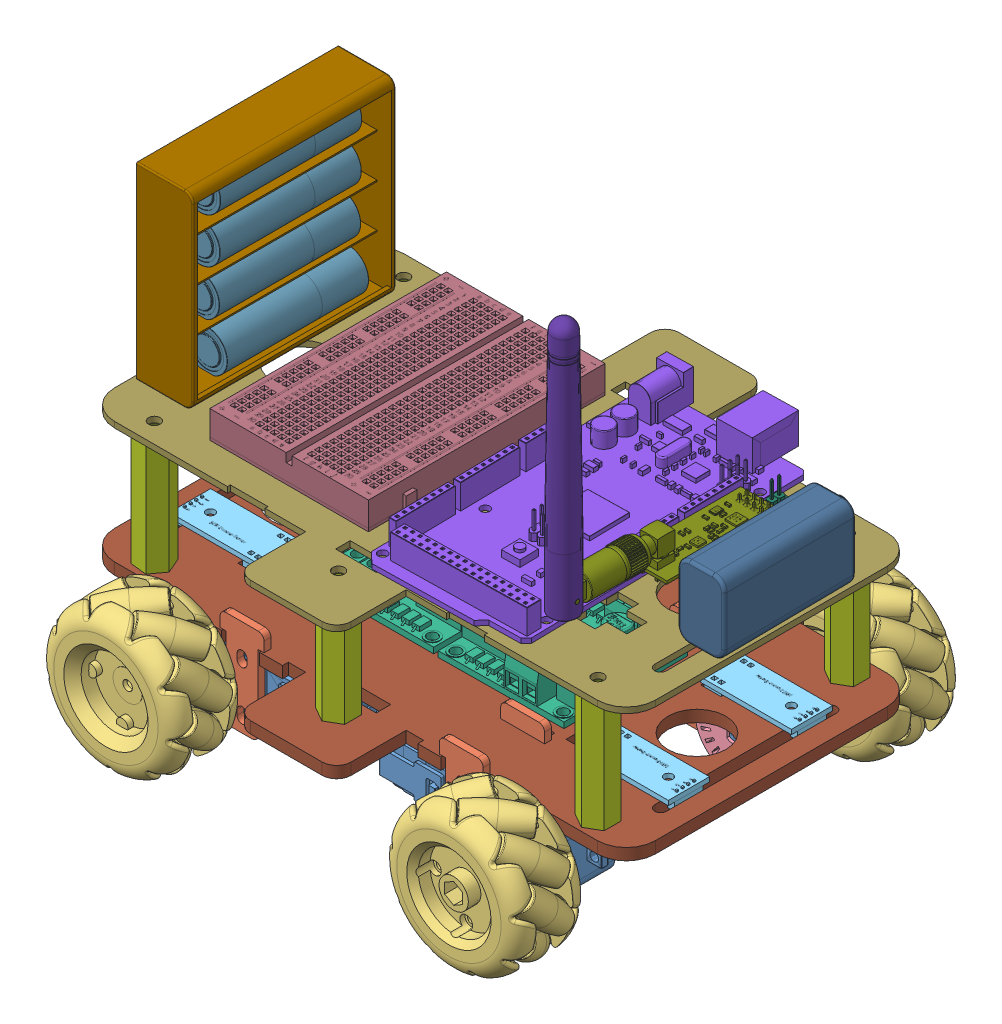
SolidWorks assembly RobotCarAssembly, configuration Default. Lengths in mm.
Overall size (187.94 185.46 154.36).
45 component instances, 17 part files, 43 mates.
Components (placement in the parent):
- Motor-1: Motor [Default] at (-116.3698 50.7185 244.6389) x (0 0 -1) z (1 0 0) size (37.1 22.45 70.35)
- Motor Stand-5: Motor Stand [Default] at (-128.5831 49.3185 244.6389) x (0 1 0) z (-1 0 0) size (33.3 2.4 15.15)
- Motor Stand-6: Motor Stand [Default] at (-128.5831 49.3185 223.4389) x (0 1 0) z (-1 0 0) size (33.3 2.4 15.15)
- Mecanum Left-1: Mecanum Left [Default] at (-142.3698 61.9185 266.4618) x (0 1 0) z (1 0 0) size (49.38 25 49.17)
- encoder20p-2: encoder20p [Predeterminado] at (-142.7381 61.8113 218.2185) x (1 0 0) z (0 0 -1) size (25.6 25.6 3.5)
- Lm393 Motor Speed Measuring Sensor Module-2: Lm393 Motor Speed Measuring Sensor Module [Default] at (-153.6231 78.7637 216.7144) x (-1 0 0) z (0 0 1) size (38.1 12.3 14.2)
- L298N-2: L298N [Default] at (-60.6738 77.1185 196.6466) x (-0.009989 0 -0.99995) z (0.99995 0 -0.009989) size (43 28.01 43)
- L298N-3: L298N [Default] at (-105.3237 77.1185 196.5696) x (0 0 1) z (-1 0 0) size (43 28.01 43)
- StandOffs-1: StandOffs [Default] at (-159.6669 77.1185 238.6389) x (-0.916026 0 0.401119) z (0 1 0) size (10 11.55 40)
- StandOffs-2: StandOffs [Default] at (-6.5177 77.1185 152.5697) x (-1 0 0) z (0 1 0) size (10 11.55 40)
- StandOffs-3: StandOffs [Default] at (-159.6669 77.1185 152.5697) x (-0.989331 0 -0.145683) z (0 1 0) size (10 11.55 40)
- StandOffs-4: StandOffs [Default] at (-6.5177 77.1185 238.6389) x (-1 0 0) z (0 1 0) size (10 11.55 40)
- StandOffs-5: StandOffs [Default] at (-83.0923 77.1185 251.6389) x (-1 0 0) z (0 1 0) size (10 11.55 40)
- StandOffs-6: StandOffs [Default] at (-83.0923 77.1185 139.6389) x (-1 0 0) z (0 1 0) size (10 11.55 40)
- Arduino Mega 2560-1: Arduino Mega 2560 [Default] at (-55.6757 120.7695 194.1341) x (-0.018928 0 -0.999821) z (0 -1 0) size (107.95 53.42 12.95)
- Battery Holder-1: Battery Holder [Default] at (-175.0329 151.6185 194.4484) x (0 -1 0) z (0 0 1) size (65 19.5 70)
- 9V-2-1: 9V-2 [Default] at (3.4952 131.6185 213.1599) x (0 -1 0) z (0.999927 0 -0.012056) size (25 49.55 16)
- ChassisBottom-1: ChassisBottom [LH] at (-87.5177 77.1185 196.2389) x (0 0 -1) z (0 -1 0) size (148 186.7 4)
- Motor-2: Motor [Default] at (-116.3698 73.1185 146.3201) x (0 0 1) z (1 0 0) size (37.1 22.45 70.35)
- Lm393 Motor Speed Measuring Sensor Module-3: Lm393 Motor Speed Measuring Sensor Module [Default] at (-153.6231 78.7637 174.2446) x (-1 0 0) z (0 0 1) size (38.1 12.3 14.2)
- encoder20p-3: encoder20p [Predeterminado] at (-142.7381 61.8113 172.7404) x (-1 0 0) z (0 0 1) size (25.6 25.6 3.5)
- Mecanum Left-2: Mecanum Left [Default] at (-142.3698 61.9185 137.0971) x (0 1 0) z (1 0 0) size (49.38 25 49.17)
- Motor Stand-7: Motor Stand [Default] at (-113.4331 49.3185 167.5201) x (0 1 0) z (1 0 0) size (33.3 2.4 15.15)
- Motor Stand-8: Motor Stand [Default] at (-113.4331 49.3185 146.3201) x (0 1 0) z (1 0 0) size (33.3 2.4 15.15)
- Motor-3: Motor [Default] at (-49.9806 73.1185 244.6389) x (0 0 -1) z (-1 0 0) size (37.1 22.45 70.35)
- Lm393 Motor Speed Measuring Sensor Module-4: Lm393 Motor Speed Measuring Sensor Module [Default] at (-12.7273 78.7637 216.7144) x (1 0 0) z (0 0 -1) size (38.1 12.3 14.2)
- encoder20p-4: encoder20p [Predeterminado] at (-23.6123 61.8113 218.2185) x (1 0 0) z (0 0 -1) size (25.6 25.6 3.5)
- Mecanum Left-3: Mecanum Left [Default] at (-23.9806 61.9185 253.8618) x (0 1 0) z (-1 0 0) size (49.38 25 49.17)
- Motor Stand-9: Motor Stand [Default] at (-52.9173 49.3185 223.4389) x (0 1 0) z (-1 0 0) size (33.3 2.4 15.15)
- Motor Stand-10: Motor Stand [Default] at (-52.9173 49.3185 244.6389) x (0 1 0) z (-1 0 0) size (33.3 2.4 15.15)
- Motor-4: Motor [Default] at (-49.9806 50.7185 146.3201) x (0 0 1) z (-1 0 0) size (37.1 22.45 70.35)
- Lm393 Motor Speed Measuring Sensor Module-5: Lm393 Motor Speed Measuring Sensor Module [Default] at (-12.7273 78.7637 174.2446) x (1 0 0) z (0 0 -1) size (38.1 12.3 14.2)
- encoder20p-5: encoder20p [Predeterminado] at (-23.6123 61.8113 172.7404) x (-1 0 0) z (0 0 1) size (25.6 25.6 3.5)
- Mecanum Left-4: Mecanum Left [Default] at (-23.9806 61.9185 124.4971) x (0 1 0) z (-1 0 0) size (49.38 25 49.17)
- Motor Stand-11: Motor Stand [Default] at (-37.7673 49.3185 167.5201) x (0 1 0) z (1 0 0) size (33.3 2.4 15.15)
- Motor Stand-12: Motor Stand [Default] at (-37.7673 49.3185 146.3201) x (0 1 0) z (1 0 0) size (33.3 2.4 15.15)
- ChassisTop-1: ChassisTop [LH] at (-87.5177 119.1185 196.2389) x (0 0 -1) z (0 -1 0) size (148 186.7 2)
- HalfBreadboard.step-1: HalfBreadboard.step [Default] at (-75.0349 124.3685 194.0056) size (56.08 9.51 83.01)
- AA Duracell Body-1: AA Duracell Body [Default] at (-163.8219 127.0806 216.5402) x (-0.999927 -0.012095 0) z (0.012095 -0.999927 0) size (14.01 50.25 14)
- AA Duracell Body-2: AA Duracell Body [Default] at (-165.8106 143.3099 217.284) x (-0.999927 -0.012095 0) z (0.012095 -0.999927 0) size (14.01 50.25 14)
- AA Duracell Body-3: AA Duracell Body [Default] at (-164.6728 175.5129 218.0278) x (-0.999927 -0.012095 0) z (0.012095 -0.999927 0) size (14.01 50.25 14)
- AA Duracell Body-4: AA Duracell Body [Default] at (-165.5815 159.1611 217.284) x (-0.999927 -0.012095 0) z (0.012095 -0.999927 0) size (14.01 50.25 14)
- NRFL24L01_Power_Board_asm-1: NRFL24L01_Power_Board_asm [Default] at (-16.8593 120.5785 167.8597) size (18.6 11.5 26)
- NRF24L01L+Antenna-1: NRF24L01L+Antenna [Default] at (-16.1243 133.1185 172.0247) x (0 0 1) z (-1 0 0) size (71.65 20.74 15.5)
- Antenna-1: Antenna [Default] at (-16.0743 71.4685 248.1747) x (0 1 0) z (-1 0 0) size (87.5 9.5 9.5)
Mates (geometry in assembly coordinates):
- Coincident16: coincident anti-aligned: plane of Motor-1 through (-153.1698 73.1185 244.6389) normal (0 1 0); plane of ChassisBottom-1 through (-176.4423 73.1185 195.6389) normal (0 -1 0)
- Coincident22: coincident anti-aligned: plane of Motor Stand-5 through (-128.5831 77.1185 247.0389) normal (0 -1 0); plane of ChassisBottom-1 through (-176.4423 77.1185 195.6389) normal (0 1 0)
- Coincident23: coincident anti-aligned: plane of Motor Stand-5 through (-128.5831 49.3185 244.6389) normal (0 0 -1); plane of ChassisBottom-1 through (-127.4423 73.1185 244.6389) normal (0 0 1)
- Coincident8: coincident anti-aligned: plane of Motor-1 through (-134.7698 61.9185 244.6389) normal (0 0 1); plane of Motor Stand-5 through (-128.5831 49.3185 244.6389) normal (0 0 -1)
- Concentric2: concentric aligned: circle of Motor-1; circle of Mecanum Left-1
- Coincident27: coincident anti-aligned: plane of Motor Stand-6 through (-128.5831 77.1185 225.8389) normal (0 -1 0); plane of ChassisBottom-1 through (-176.4423 77.1185 195.6389) normal (0 1 0)
- Coincident28: coincident aligned: line of Motor Stand-5 through (-115.4331 82.6185 247.0389) axis (0 0 -1); line of Motor Stand-6 through (-115.4331 82.6185 225.8389) axis (0 0 -1)
- Coincident30: coincident anti-aligned: plane of Motor Stand-6 through (-128.5831 49.3185 225.8389) normal (0 0 1); plane of ChassisBottom-1 through (-126.9423 73.1185 225.8389) normal (0 0 -1)
- Lock3: lock: unknown of Motor-1; unknown of Mecanum Left-1
- Lock7: lock: unknown of Motor-1; unknown of encoder20p-2
- Lock8: lock: unknown of encoder20p-2; unknown of Lm393 Motor Speed Measuring Sensor Module-2
- Concentric6: concentric anti-aligned: circle of ChassisBottom-1; circle of L298N-2
- Coincident31: coincident anti-aligned: plane of ChassisBottom-1 through (-176.4423 77.1185 195.6389) normal (0 1 0); plane of L298N-2 through (-60.6738 77.1185 196.6466) normal (0 -1 0)
- Concentric9: concentric aligned: circle of ChassisBottom-1; circle of L298N-3
- Coincident32: coincident anti-aligned: plane of ChassisBottom-1 through (-176.4423 77.1185 195.6389) normal (0 1 0); plane of L298N-3 through (-105.3237 77.1185 196.5696) normal (0 -1 0)
- Lock9: lock: unknown of Motor-1; unknown of ChassisBottom-1
- Lock11: lock: unknown of ChassisBottom-1; unknown of Motor-4
- Lock12: lock: unknown of ChassisBottom-1; unknown of Motor-3
- Concentric10: concentric anti-aligned: circle of StandOffs-1; circle of ChassisBottom-1
- Coincident38: coincident anti-aligned: plane of StandOffs-1 through (-159.6669 77.1185 238.6389) normal (0 -1 0); plane of ChassisBottom-1 through (-176.4423 77.1185 195.6389) normal (0 1 0)
- Coincident39: coincident anti-aligned: plane of StandOffs-3 through (-159.6669 77.1185 152.5697) normal (0 -1 0); plane of ChassisBottom-1 through (-176.4423 77.1185 195.6389) normal (0 1 0)
- Concentric11: concentric anti-aligned: circle of StandOffs-3; circle of ChassisBottom-1
- Concentric12: concentric aligned: circle of StandOffs-5; circle of ChassisBottom-1
- Concentric13: concentric aligned: circle of StandOffs-6; circle of ChassisBottom-1
- Concentric14: concentric aligned: circle of StandOffs-4; circle of ChassisBottom-1
- Concentric15: concentric aligned: circle of StandOffs-2; circle of ChassisBottom-1
- Concentric17: concentric aligned: circle of StandOffs-3; circle of ChassisTop-1
- Concentric18: concentric anti-aligned: circle of StandOffs-4; circle of ChassisTop-1
- Coincident41: coincident anti-aligned: plane of StandOffs-6 through (-83.0923 77.1185 139.6389) normal (0 -1 0); plane of ChassisBottom-1 through (-176.4423 77.1185 195.6389) normal (0 1 0)
- Coincident42: coincident anti-aligned: plane of StandOffs-2 through (-6.5177 77.1185 152.5697) normal (0 -1 0); plane of ChassisBottom-1 through (-176.4423 77.1185 195.6389) normal (0 1 0)
- Coincident43: coincident anti-aligned: plane of StandOffs-4 through (-6.5177 77.1185 238.6389) normal (0 -1 0); plane of ChassisBottom-1 through (-176.4423 77.1185 195.6389) normal (0 1 0)
- Coincident44: coincident anti-aligned: plane of StandOffs-5 through (-83.0923 77.1185 251.6389) normal (0 -1 0); plane of ChassisBottom-1 through (-176.4423 77.1185 195.6389) normal (0 1 0)
- Coincident45: coincident anti-aligned: plane of StandOffs-5 through (-83.0923 117.1185 251.6389) normal (0 1 0); plane of ChassisTop-1 through (-176.4423 117.1185 195.6389) normal (0 -1 0)
- Coincident47: coincident anti-aligned: plane of Arduino Mega 2560-1 through (-83.3406 119.1185 143.8488) normal (0 -1 0); plane of ChassisTop-1 through (-176.4423 119.1185 195.6389) normal (0 1 0)
- Coincident49: coincident anti-aligned: plane of ChassisTop-1 through (-176.4423 119.1185 195.6389) normal (0 1 0); plane of HalfBreadboard.step-1 through (-116.9449 119.1185 152.0956) normal (0 -1 0)
- Coincident51: coincident anti-aligned: plane of Battery Holder-1 through (-155.5329 119.1185 159.4484) normal (0 -1 0); plane of ChassisTop-1 through (-176.4423 119.1185 195.6389) normal (0 1 0)
- Coincident52: coincident anti-aligned: plane of 9V-2-1 through (10.94 119.1185 167.0668) normal (0 -1 0); plane of ChassisTop-1 through (-176.4423 119.1185 195.6389) normal (0 1 0)
- Coincident57: coincident anti-aligned: plane of NRFL24L01_Power_Board_asm-1 through (-14.3193 122.1185 173.5297) normal (0 0 1); plane of NRF24L01L+Antenna-1 through (-12.0493 124.6185 173.5297) normal (0 0 -1)
- Coincident58: coincident anti-aligned: plane of NRFL24L01_Power_Board_asm-1 through (-12.0493 132.8727 173.5297) normal (-1 0 0); plane of NRF24L01L+Antenna-1 through (-12.0493 124.6185 173.5297) normal (1 0 0)
- Coincident59: coincident anti-aligned: plane of NRFL24L01_Power_Board_asm-1 through (-14.3193 130.6185 175.3197) normal (0 1 0); plane of NRF24L01L+Antenna-1 through (-16.1243 130.6185 172.0247) normal (0 -1 0)
- Coincident60: coincident anti-aligned: plane of ChassisTop-1 through (-176.4423 119.1185 195.6389) normal (0 1 0); plane of NRFL24L01_Power_Board_asm-1 through (-24.7893 119.1185 159.1097) normal (0 -1 0)
- Concentric19: concentric aligned: circle of NRF24L01L+Antenna-1; circle of Antenna-1
- Coincident61: coincident anti-aligned: plane of NRF24L01L+Antenna-1 through (-18.9243 140.3685 240.9247) normal (-1 0 0); plane of Antenna-1 through (-18.9243 135.3685 244.4247) normal (1 0 0)
